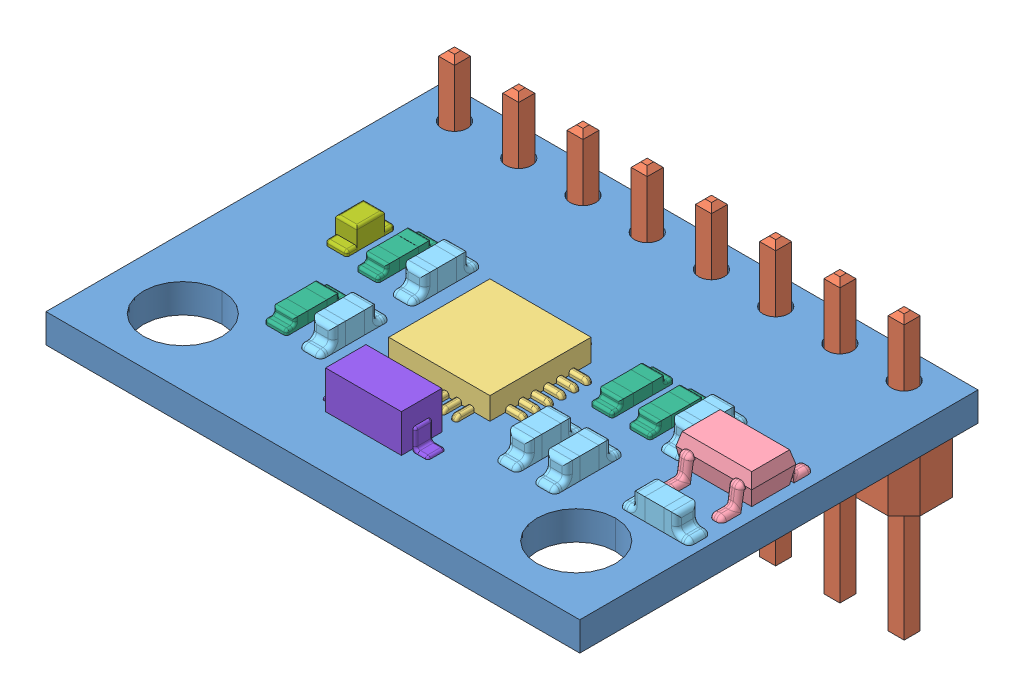
SolidWorks assembly MPU 6050 IMU.STEP, configuration Default. Lengths in mm.
Overall size (21.11 11.18 15.88).
23 component instances, 8 part files, 0 mates.
Components (placement in the parent):
- Base.STEP-1: Base.STEP [Default] at (7.2489 10.9584 16.5726) size (21.11 1.14 15.75)
- pin header.STEP-1: pin header.STEP [Default] at (16.0246 10.3869 9.8416) x (-1 0 0) z (0 0 1) size (2.54 11.18 2.54)
- pin header.STEP-2: pin header.STEP [Default] at (13.4846 10.3869 9.8416) x (-1 0 0) z (0 0 1) size (2.54 11.18 2.54)
- pin header.STEP-3: pin header.STEP [Default] at (10.9446 10.3869 9.8416) x (-1 0 0) z (0 0 1) size (2.54 11.18 2.54)
- pin header.STEP-4: pin header.STEP [Default] at (8.4046 10.3869 9.8416) x (-1 0 0) z (0 0 1) size (2.54 11.18 2.54)
- pin header.STEP-5: pin header.STEP [Default] at (5.8646 10.3869 9.8416) x (-1 0 0) z (0 0 1) size (2.54 11.18 2.54)
- pin header.STEP-6: pin header.STEP [Default] at (3.3246 10.3869 9.8416) x (-1 0 0) z (0 0 1) size (2.54 11.18 2.54)
- pin header.STEP-7: pin header.STEP [Default] at (0.7846 10.3869 9.8416) x (-1 0 0) z (0 0 1) size (2.54 11.18 2.54)
- pin header.STEP-8: pin header.STEP [Default] at (-1.7554 10.3869 9.8416) x (-1 0 0) z (0 0 1) size (2.54 11.18 2.54)
- sensor chip.STEP-1: sensor chip.STEP [Default] at (7.2489 11.5499 17.4466) size (5.4 0.9 5.4)
- S2NH chip.STEP-1: S2NH chip.STEP [Default] at (16.1026 12.3799 16.5726) size (3 1.35 3.65)
- Resistor small.STEP-1: Resistor small.STEP [Default] at (16.1026 11.5314 19.3726) size (2.75 0.94 0.95)
- Resistor small.STEP-2: Resistor small.STEP [Default] at (13.9776 11.5314 15.6976) x (0 0 -1) z (1 0 0) size (2.75 0.94 0.95)
- Resistor small black.STEP-1: Resistor small black.STEP [Default] at (12.6276 11.5299 15.6976) x (0 0 1) z (-1 0 0) size (2.45 0.54 0.95)
- Resistor small black.STEP-2: Resistor small black.STEP [Default] at (11.1276 11.5299 15.6976) x (0 0 1) z (-1 0 0) size (2.45 0.54 0.95)
- Resistor small.STEP-3: Resistor small.STEP [Default] at (12.6276 11.5314 19.3216) x (0 0 -1) z (1 0 0) size (2.75 0.94 0.95)
- Resistor small.STEP-4: Resistor small.STEP [Default] at (11.1276 11.5314 19.3216) x (0 0 -1) z (1 0 0) size (2.75 0.94 0.95)
- Resistor small.STEP-5: Resistor small.STEP [Default] at (3.3702 11.5314 19.3216) x (0 0 -1) z (1 0 0) size (2.75 0.94 0.95)
- Resistor small black.STEP-3: Resistor small black.STEP [Default] at (1.8702 11.5299 15.6968) x (0 0 -1) z (1 0 0) size (2.45 0.54 0.95)
- Resistor small.STEP-6: Resistor small.STEP [Default] at (3.3702 11.5314 15.6976) x (0 0 1) z (-1 0 0) size (2.75 0.94 0.95)
- Small LED.STEP-1: Small LED.STEP [Default] at (0.3652 11.5299 15.6976) size (0.85 0.84 1.9)
- Resistor small black.STEP-4: Resistor small black.STEP [Default] at (1.8702 11.5299 19.3216) x (0 0 1) z (-1 0 0) size (2.45 0.54 0.95)
- Resistor black.STEP-1: Resistor black.STEP [Default] at (7.2489 12.3799 21.6466) size (4.2 1.6 1.6)
